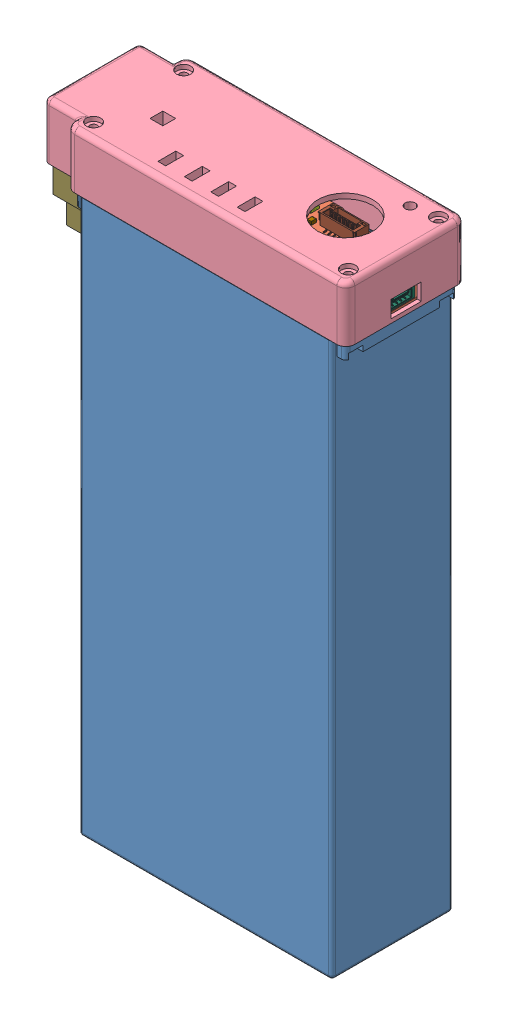
SolidWorks assembly 总装, configuration 默认. Lengths in mm.
Overall size (93.2 180.5 42.06).
174 component instances, 30 part files, 34 mates.
Components (placement in the parent):
- 电池组主外壳-1: 电池组主外壳 [默认] at origin size (80.2 164 35.9)
- 32700_cell-1: 32700_cell [默认] at (71.5 16.1 -16.1) x (0 0 1) z (0 -1 0) size (32.2 70.6 32.2)
- 32700_cell-2: 32700_cell [默认] at (0.9 48.3 -16.1) x (0 0 -1) z (0 -1 0) size (32.2 70.6 32.2)
- 32700_cell-3: 32700_cell [默认] at (71.5 80.5 -16.1) x (0 -0.381849 0.924225) z (0 -0.924225 -0.381849) size (32.2 70.6 32.2)
- 32700_cell-4: 32700_cell [默认] at (0.9 112.7 -16.1) x (0 0.381849 -0.924225) z (0 -0.924225 -0.381849) size (32.2 70.6 32.2)
- 32700_cell-5: 32700_cell [默认] at (71.5 144.9 -16.1) x (0 -0.38232 0.92403) z (0 -0.92403 -0.38232) size (32.2 70.6 32.2)
- 铜带45x10x0.45-1: 铜带45x10x0.45 [默认] at (0.9 9.7 -11.1) x (0 1 0) z (0 0 1) size (45 0.45 10)
- 铜带45x10x0.45-2: 铜带45x10x0.45 [默认] at (71.5 86.9 -11.1) x (0 -1 0) z (0 0 1) size (45 0.45 10)
- 铜带45x10x0.45-3: 铜带45x10x0.45 [默认] at (0.9 74.1 -11.1) x (0 1 0) z (0 0 1) size (45 0.45 10)
- 铜带45x10x0.45-4: 铜带45x10x0.45 [默认] at (71.95 106.3 -11.1) x (0 1 0) z (0 0 1) size (45 0.45 10)
- 面板盖-1: 面板盖 [默认] at (31.3994 162.5 -15.9507) size (93.2 16.5 35.7)
- 3D_PCB2_2026-02-08-1: 3D_PCB2_2026-02-08 [默认] at (-4.1002 162.5 0.0001) x (1 0 0) z (0 1 0) size (90.37 32.87 28.1)
  - 3D_PCB2_2026-02-08.step-1: 3D_PCB2_2026-02-08.step [默认] at origin size (90.37 32.87 15)
    - WmRV-R84-R2512.step-1: WmRV-R84-R2512.step [默认] at (22.1172 24.7766 1.6001) x (0 1 0) z (0 0 1) size (6.3 3.2 0.61)
      - COMPOUND.step-1: COMPOUND.step [默认] at origin size (6.3 3.2 0.61)
    - WmRV-R3-R0603.step-1: WmRV-R3-R0603.step [默认] at (27.4493 25.0191 1.6001) x (-1 0 0) z (0 0 1) size (1.62 0.81 0.45)
      - COMPOUND-0.step-1: COMPOUND-0.step [默认] at origin size (1.62 0.81 0.45)
    - WmRV-R4-R0603.step-1: WmRV-R4-R0603.step [默认] at (27.4321 26.4161 1.6001) x (-1 0 0) z (0 0 1) size (1.62 0.81 0.45)
      - COMPOUND-0.step-1: COMPOUND-0.step [默认] at origin size (1.62 0.81 0.45)
    - WmRV-R5-R0603.step-1: WmRV-R5-R0603.step [默认] at (30.3531 26.4161 1.6001) size (1.62 0.81 0.45)
      - COMPOUND-0.step-1: COMPOUND-0.step [默认] at origin size (1.62 0.81 0.45)
    - WmRV-R6-R0603.step-1: WmRV-R6-R0603.step [默认] at (30.3531 25.0191 1.6001) size (1.62 0.81 0.45)
      - COMPOUND-0.step-1: COMPOUND-0.step [默认] at origin size (1.62 0.81 0.45)
    - WmRV-R8-R0603.step-1: WmRV-R8-R0603.step [默认] at (30.3853 22.1925 1.6001) size (1.62 0.81 0.45)
      - COMPOUND-0.step-1: COMPOUND-0.step [默认] at origin size (1.62 0.81 0.45)
    - WmRV-R9-R0603.step-1: WmRV-R9-R0603.step [默认] at (30.3531 20.828 1.6001) size (1.62 0.81 0.45)
      - COMPOUND-0.step-1: COMPOUND-0.step [默认] at origin size (1.62 0.81 0.45)
    - WmRV-R10-R0603.step-1: WmRV-R10-R0603.step [默认] at (27.4321 22.225 1.6001) x (-1 0 0) z (0 0 1) size (1.62 0.81 0.45)
      - COMPOUND-0.step-1: COMPOUND-0.step [默认] at origin size (1.62 0.81 0.45)
    - WmRV-R11-R0603.step-1: WmRV-R11-R0603.step [默认] at (27.4321 20.828 1.6001) x (-1 0 0) z (0 0 1) size (1.62 0.81 0.45)
      - COMPOUND-0.step-1: COMPOUND-0.step [默认] at origin size (1.62 0.81 0.45)
    - WmRV-R12-R0603.step-1: WmRV-R12-R0603.step [默认] at (33.9091 16.383 1.6001) x (0 1 0) z (0 0 1) size (1.62 0.81 0.45)
      - COMPOUND-0.step-1: COMPOUND-0.step [默认] at origin size (1.62 0.81 0.45)
    - WmRV-R13-R0603.step-1: WmRV-R13-R0603.step [默认] at (35.3061 16.383 1.6001) x (0 1 0) z (0 0 1) size (1.62 0.81 0.45)
      - COMPOUND-0.step-1: COMPOUND-0.step [默认] at origin size (1.62 0.81 0.45)
    - WmRV-R20-R0603.step-1: WmRV-R20-R0603.step [默认] at (26.8015 15.6931 1.6001) size (1.62 0.81 0.45)
      - COMPOUND-0.step-1: COMPOUND-0.step [默认] at origin size (1.62 0.81 0.45)
    - WmRV-R21-R0603.step-1: WmRV-R21-R0603.step [默认] at (26.7894 17.2153 1.6001) size (1.62 0.81 0.45)
      - COMPOUND-0.step-1: COMPOUND-0.step [默认] at origin size (1.62 0.81 0.45)
    - WmRV-R22-R0603.step-1: WmRV-R22-R0603.step [默认] at (37.4651 27.5591 1.6001) x (0 -1 0) z (0 0 1) size (1.62 0.81 0.45)
      - COMPOUND-0.step-1: COMPOUND-0.step [默认] at origin size (1.62 0.81 0.45)
    - WmRV-R23-R0603.step-1: WmRV-R23-R0603.step [默认] at (38.8621 27.5591 1.6001) x (0 -1 0) z (0 0 1) size (1.62 0.81 0.45)
      - COMPOUND-0.step-1: COMPOUND-0.step [默认] at origin size (1.62 0.81 0.45)
    - WmRV-R24-R0603.step-1: WmRV-R24-R0603.step [默认] at (36.0681 27.5591 1.6001) x (0 -1 0) z (0 0 1) size (1.62 0.81 0.45)
      - COMPOUND-0.step-1: COMPOUND-0.step [默认] at origin size (1.62 0.81 0.45)
    - WmRV-R25-R0603.step-1: WmRV-R25-R0603.step [默认] at (17.761 21.4915 1.6001) x (-1 0 0) z (0 0 1) size (1.62 0.81 0.45)
      - COMPOUND-0.step-1: COMPOUND-0.step [默认] at origin size (1.62 0.81 0.45)
    - WmRV-R26-R0603.step-1: WmRV-R26-R0603.step [默认] at (39.5952 29.8217 1.6001) x (-1 0 0) z (0 0 1) size (1.62 0.81 0.45)
      - COMPOUND-0.step-1: COMPOUND-0.step [默认] at origin size (1.62 0.81 0.45)
    - WmRV-R27-R0603.step-1: WmRV-R27-R0603.step [默认] at (40.2591 27.5591 1.6001) x (0 -1 0) z (0 0 1) size (1.62 0.81 0.45)
      - COMPOUND-0.step-1: COMPOUND-0.step [默认] at origin size (1.62 0.81 0.45)
    - WmRV-R31-R0603.step-1: WmRV-R31-R0603.step [默认] at (47.0294 12.1883 1.6001) x (0 1 0) z (0 0 1) size (1.62 0.81 0.45)
      - COMPOUND-0.step-1: COMPOUND-0.step [默认] at origin size (1.62 0.81 0.45)
    - WmRV-R32-R0603.step-1: WmRV-R32-R0603.step [默认] at (45.3784 12.1883 1.6001) x (0 1 0) z (0 0 1) size (1.62 0.81 0.45)
      - COMPOUND-0.step-1: COMPOUND-0.step [默认] at origin size (1.62 0.81 0.45)
    - WmRV-R33-R0603.step-1: WmRV-R33-R0603.step [默认] at (50.3315 12.1883 1.6001) x (0 1 0) z (0 0 1) size (1.62 0.81 0.45)
      - COMPOUND-0.step-1: COMPOUND-0.step [默认] at origin size (1.62 0.81 0.45)
    - WmRV-R34-R0603.step-1: WmRV-R34-R0603.step [默认] at (48.6804 12.1883 1.6001) x (0 1 0) z (0 0 1) size (1.62 0.81 0.45)
      - COMPOUND-0.step-1: COMPOUND-0.step [默认] at origin size (1.62 0.81 0.45)
    - WmRV-R35-R0603.step-1: WmRV-R35-R0603.step [默认] at (53.6335 12.1883 1.6001) x (0 1 0) z (0 0 1) size (1.62 0.81 0.45)
      - COMPOUND-0.step-1: COMPOUND-0.step [默认] at origin size (1.62 0.81 0.45)
    - WmRV-R36-R0603.step-1: WmRV-R36-R0603.step [默认] at (51.9825 12.1883 1.6001) x (0 1 0) z (0 0 1) size (1.62 0.81 0.45)
      - COMPOUND-0.step-1: COMPOUND-0.step [默认] at origin size (1.62 0.81 0.45)
    - WmRV-R37-R0603.step-1: WmRV-R37-R0603.step [默认] at (56.9355 12.1883 1.6001) x (0 1 0) z (0 0 1) size (1.62 0.81 0.45)
      - COMPOUND-0.step-1: COMPOUND-0.step [默认] at origin size (1.62 0.81 0.45)
    - WmRV-R38-R0603.step-1: WmRV-R38-R0603.step [默认] at (55.2845 12.1883 1.6001) x (0 1 0) z (0 0 1) size (1.62 0.81 0.45)
      - COMPOUND-0.step-1: COMPOUND-0.step [默认] at origin size (1.62 0.81 0.45)
    - WmRV-R39-R0603.step-1: WmRV-R39-R0603.step [默认] at (60.2375 12.1883 1.6001) x (0 1 0) z (0 0 1) size (1.62 0.81 0.45)
      - COMPOUND-0.step-1: COMPOUND-0.step [默认] at origin size (1.62 0.81 0.45)
    - WmRV-R40-R0603.step-1: WmRV-R40-R0603.step [默认] at (58.5865 12.1883 1.6001) x (0 1 0) z (0 0 1) size (1.62 0.81 0.45)
      - COMPOUND-0.step-1: COMPOUND-0.step [默认] at origin size (1.62 0.81 0.45)
    - WmRV-R15-R0603.step-1: WmRV-R15-R0603.step [默认] at (36.4491 12.065 1.6001) x (-1 0 0) z (0 0 1) size (1.62 0.81 0.45)
      - COMPOUND-0.step-1: COMPOUND-0.step [默认] at origin size (1.62 0.81 0.45)
    - WmRV-R17-R0603.step-1: WmRV-R17-R0603.step [默认] at (32.7017 12.2384 1.6001) size (1.62 0.81 0.45)
      - COMPOUND-0.step-1: COMPOUND-0.step [默认] at origin size (1.62 0.81 0.45)
    - WmRV-R79-R0603.step-1: WmRV-R79-R0603.step [默认] at (33.0941 5.1797 1.6001) x (0 1 0) z (0 0 1) size (1.62 0.81 0.45)
      - COMPOUND-0.step-1: COMPOUND-0.step [默认] at origin size (1.62 0.81 0.45)
    - WmRV-R80-R0603.step-1: WmRV-R80-R0603.step [默认] at (25.3019 5.1441 1.6001) x (0 1 0) z (0 0 1) size (1.62 0.81 0.45)
      - COMPOUND-0.step-1: COMPOUND-0.step [默认] at origin size (1.62 0.81 0.45)
    - WmRV-R81-R0603.step-1: WmRV-R81-R0603.step [默认] at (48.7218 4.9516 1.6001) x (0 1 0) z (0 0 1) size (1.62 0.81 0.45)
      - COMPOUND-0.step-1: COMPOUND-0.step [默认] at origin size (1.62 0.81 0.45)
    - WmRV-R82-R0603.step-1: WmRV-R82-R0603.step [默认] at (41.0176 5.0593 1.6001) x (0 1 0) z (0 0 1) size (1.62 0.81 0.45)
      - COMPOUND-0.step-1: COMPOUND-0.step [默认] at origin size (1.62 0.81 0.45)
    - WmRV-R86-R0603.step-1: WmRV-R86-R0603.step [默认] at (74.961 22.2365 1.6001) x (0 -1 0) z (0 0 1) size (1.62 0.81 0.45)
      - COMPOUND-0.step-1: COMPOUND-0.step [默认] at origin size (1.62 0.81 0.45)
    - WmRV-R85-R0603.step-1: WmRV-R85-R0603.step [默认] at (68.0472 12.6732 1.6001) x (0 -1 0) z (0 0 1) size (1.62 0.81 0.45)
      - COMPOUND-0.step-1: COMPOUND-0.step [默认] at origin size (1.62 0.81 0.45)
    - WmRV-R87-R0603.step-1: WmRV-R87-R0603.step [默认] at (15.6463 12.7266 1.6001) x (0 1 0) z (0 0 1) size (1.62 0.81 0.45)
      - COMPOUND-0.step-1: COMPOUND-0.step [默认] at origin size (1.62 0.81 0.45)
    - WmRV-R88-R0603.step-1: WmRV-R88-R0603.step [默认] at (60.1459 23.4729 1.6001) size (1.62 0.81 0.45)
      - COMPOUND-0.step-1: COMPOUND-0.step [默认] at origin size (1.62 0.81 0.45)
    - WmRV-R2-R0603.step-1: WmRV-R2-R0603.step [默认] at (30.3531 23.622 1.6001) x (-1 0 0) z (0 0 1) size (1.62 0.81 0.45)
      - COMPOUND-0.step-1: COMPOUND-0.step [默认] at origin size (1.62 0.81 0.45)
    - WmRV-SW15.step-1: WmRV-SW15.step [默认] at (70.751 28.5292 1.6001) x (-1 0 0) z (0 0 1) size (4.65 3.3 2.52)
      - SW-SMD_4P-L4.2-W3.2-P2.15-LS4.6-1.step-1: SW-SMD_4P-L4.2-W3.2-P2.15-LS4.6-1.step [默认] at origin size (4.65 3.3 2.52)
        - SOLID.step-1: SOLID.step [默认] at origin size (4.65 3.3 2.52)
        - SOLID-1.step-1: SOLID-1.step [默认] at origin size (4.2 3.3 0.19)
    - WmRV-R76-R0805.step-1: WmRV-R76-R0805.step [默认] at (42.2591 24.765 1.6001) size (2 1.3 0.61)
      - COMPOUND-2.step-1: COMPOUND-2.step [默认] at origin size (2 1.3 0.61)
    - WmRV-SW16.step-1: WmRV-SW16.step [默认] at (11.6698 14.2952 1.6001) x (-1 0 0) z (0 0 1) size (5.8 5.8 13.6)
      - SW-TH_5.8ZSGT.step-1: SW-TH_5.8ZSGT.step [默认] at origin size (5.8 5.8 13.6)
        - SOLID-3.step-1: SOLID-3.step [默认] at origin size (5.8 5.8 7.6)
        - SOLID-4.step-1: SOLID-4.step [默认] at origin size (5.8 5.8 9.74)
    - WmRV-R65-R1206.step-1: WmRV-R65-R1206.step [默认] at (49.7282 19.8084 1.6001) x (0 1 0) z (0 0 1) size (3.2 1.6 0.56)
      - COMPOUND-5.step-1: COMPOUND-5.step [默认] at origin size (3.2 1.6 0.56)
    - WmRV-R66-R1206.step-1: WmRV-R66-R1206.step [默认] at (53.062 19.8084 1.6001) x (0 1 0) z (0 0 1) size (3.2 1.6 0.56)
      - COMPOUND-5.step-1: COMPOUND-5.step [默认] at origin size (3.2 1.6 0.56)
    - WmRV-R67-R1206.step-1: WmRV-R67-R1206.step [默认] at (56.3957 19.8084 1.6001) x (0 1 0) z (0 0 1) size (3.2 1.6 0.56)
      - COMPOUND-5.step-1: COMPOUND-5.step [默认] at origin size (3.2 1.6 0.56)
    - WmRV-R68-R1206.step-1: WmRV-R68-R1206.step [默认] at (59.7295 19.8084 1.6001) x (0 1 0) z (0 0 1) size (3.2 1.6 0.56)
      - COMPOUND-5.step-1: COMPOUND-5.step [默认] at origin size (3.2 1.6 0.56)
    - WmRV-R64-R1206.step-1: WmRV-R64-R1206.step [默认] at (46.3944 19.8084 1.6001) x (0 1 0) z (0 0 1) size (3.2 1.6 0.56)
      - COMPOUND-5.step-1: COMPOUND-5.step [默认] at origin size (3.2 1.6 0.56)
    - WmRV-R16-RES-TH_L2.5-W2.5-P1.70-D0.3.step-1: WmRV-R16-RES-TH_L2.5-W2.5-P1.70-D0.3.step [默认] at (36.3221 9.906 1.6001) x (-1 0 0) z (0 0 1) size (2.52 2.5 7.2)
      - COMPOUND-6.step-1: COMPOUND-6.step [默认] at origin size (2.52 2.5 7.2)
    - WmRV-R14-RES-TH_L2.5-W2.5-P1.70-D0.3.step-1: WmRV-R14-RES-TH_L2.5-W2.5-P1.70-D0.3.step [默认] at (32.7661 9.906 1.6001) size (2.52 2.5 7.2)
      - COMPOUND-6.step-1: COMPOUND-6.step [默认] at origin size (2.52 2.5 7.2)
    - WmRV-U13-QFN-28_L4.0-W4.0-P0.40-BL-EP2.8.step-1: WmRV-U13-QFN-28_L4.0-W4.0-P0.40-BL-EP2.8.step [默认] at (70.06 17.4212 1.6001) x (-1 0 0) z (0 0 1) size (4 4 0.72)
      - COMPOUND-7.step-1: COMPOUND-7.step [默认] at origin size (4 4 0.72)
    - WmRV-U14-CONN-SMD_4P-P1.25_XUNPU_WAFER-GH1.25-4PWB.step-1: WmRV-U14-CONN-SMD_4P-P1.25_XUNPU_WAFER-GH1.25-4PWB.step [默认] at (76.8352 16.45 1.6001) x (0 1 0) z (0 0 1) size (8.25 5 4.35)
      - COMPOUND-8.step-1: COMPOUND-8.step [默认] at origin size (8.25 5 4.35)
    - WmRV-Q7-SOT-23-3_L2.9-W1.3-P1.90-LS2.4-BR.step-1: WmRV-Q7-SOT-23-3_L2.9-W1.3-P1.90-LS2.4-BR.step [默认] at (56.2111 15.5381 1.6001) x (0 -1 0) z (0 0 1) size (2.5 2.89 1.05)
      - COMPOUND-9.step-1: COMPOUND-9.step [默认] at origin size (2.5 2.89 1.05)
    - WmRV-Q8-SOT-23-3_L2.9-W1.3-P1.90-LS2.4-BR.step-1: WmRV-Q8-SOT-23-3_L2.9-W1.3-P1.90-LS2.4-BR.step [默认] at (59.5257 15.5381 1.6001) x (0 -1 0) z (0 0 1) size (2.5 2.89 1.05)
      - COMPOUND-9.step-1: COMPOUND-9.step [默认] at origin size (2.5 2.89 1.05)
    - WmRV-Q9-SOT-23-3_L2.9-W1.3-P1.90-LS2.4-BR.step-1: WmRV-Q9-SOT-23-3_L2.9-W1.3-P1.90-LS2.4-BR.step [默认] at (49.582 15.5381 1.6001) x (0 -1 0) z (0 0 1) size (2.5 2.89 1.05)
      - COMPOUND-9.step-1: COMPOUND-9.step [默认] at origin size (2.5 2.89 1.05)
    - WmRV-Q10-SOT-23-3_L2.9-W1.3-P1.90-LS2.4-BR.step-1: WmRV-Q10-SOT-23-3_L2.9-W1.3-P1.90-LS2.4-BR.step [默认] at (46.2674 15.5381 1.6001) x (0 -1 0) z (0 0 1) size (2.5 2.89 1.05)
      - COMPOUND-9.step-1: COMPOUND-9.step [默认] at origin size (2.5 2.89 1.05)
    - WmRV-Q6-SOT-23-3_L2.9-W1.3-P1.90-LS2.4-BR.step-1: WmRV-Q6-SOT-23-3_L2.9-W1.3-P1.90-LS2.4-BR.step [默认] at (52.8966 15.5381 1.6001) x (0 -1 0) z (0 0 1) size (2.5 2.89 1.05)
      - COMPOUND-9.step-1: COMPOUND-9.step [默认] at origin size (2.5 2.89 1.05)
    - WmRV-BUTTON-CONN-SMD_3P-P1.25_XUNPU_WAFER-GH1.25-3PLB.step-1: WmRV-BUTTON-CONN-SMD_3P-P1.25_XUNPU_WAFER-GH1.25-3PLB.step [默认] at (68.2638 7.662 1.6001) size (7.06 4.95 4.2)
      - COMPOUND-10.step-1: COMPOUND-10.step [默认] at origin size (7.06 4.95 4.2)
    - WmRV-U4-QFN-28_L5.0-W5.0-P0.50-TL-EP3.3.step-1: WmRV-U4-QFN-28_L5.0-W5.0-P0.50-TL-EP3.3.step [默认] at (36.0465 22.0655 1.6001) size (5 5 0.93)
      - COMPOUND-11.step-1: COMPOUND-11.step [默认] at origin size (5 5 0.93)
    - WmRV-U12-SOIC-16_L10.3-W7.5-P1.27-LS10.3-BL.step-1: WmRV-U12-SOIC-16_L10.3-W7.5-P1.27-LS10.3-BL.step [默认] at (13.7371 5.7123 1.6001) x (0 1 0) z (0 0 1) size (10.3 10.41 2.85)
      - COMPOUND-12.step-1: COMPOUND-12.step [默认] at origin size (10.3 10.41 2.85)
    - WmRV-Board.step-1: WmRV-Board.step [默认] at origin size (90.37 32.87 1.6)
    - WmRV-D2-SMA_L4.2-W2.6-LS5.0-RD_1.step-1: WmRV-D2-SMA_L4.2-W2.6-LS5.0-RD_1.step [默认] at (9.9917 21.1675 1.6001) size (5 2.57 2.05)
    - WmRV-C33-C0805.step-1: WmRV-C33-C0805.step [默认] at (42.4181 22.733 1.6001) x (-1 0 0) z (0 0 1) size (2 1.3 1.3)
    - WmRV-Q11-DFN-8_L5.8-W4.9-P1.27-LS6.1-BL-2.step-1: WmRV-Q11-DFN-8_L5.8-W4.9-P1.27-LS6.1-BL-2.step [默认] at (15.7047 25.2897 1.6001) x (0 1 0) z (0 0 1) size (5.15 6.1 1.03)
    - WmRV-Q11-DFN-8_L5.8-W4.9-P1.27-LS6.1-BL-2.step-2: WmRV-Q11-DFN-8_L5.8-W4.9-P1.27-LS6.1-BL-2.step [默认] at (8.6597 25.278 1.6001) x (0 -1 0) z (0 0 1) size (5.15 6.1 1.03)
    - WmRV-X2-CRYSTAL-SMD_4P-L3.2-W2.5-BL.step-1: WmRV-X2-CRYSTAL-SMD_4P-L3.2-W2.5-BL.step [默认] at (70.695 22.5012 1.6001) x (-1 0 0) z (0 0 1) size (3.2 2.5 0.7)
    - WmRV-D50-SOD-123FL_L2.7-W1.8-LS3.8-RD.step-1: WmRV-D50-SOD-123FL_L2.7-W1.8-LS3.8-RD.step [默认] at (42.1641 28.0671 1.6001) x (0 1 0) z (0 0 1) size (3.7 1.8 1.14)
    - WmRV-LED5-LED-TH_L5.0-W2.5-P2.54-FD_GREEN_XL-257SYGD-L.step-1: WmRV-LED5-LED-TH_L5.0-W2.5-P2.54-FD_GREEN_XL-257SYGD-L.step [默认] at (38.7774 5.207 1.6001) x (0 1 0) z (0 0 1) size (5 2.5 15)
    - WmRV-LED5-LED-TH_L5.0-W2.5-P2.54-FD_GREEN_XL-257SYGD-L.step-2: WmRV-LED5-LED-TH_L5.0-W2.5-P2.54-FD_GREEN_XL-257SYGD-L.step [默认] at (30.9457 5.207 1.6001) x (0 1 0) z (0 0 1) size (5 2.5 15)
    - WmRV-LED5-LED-TH_L5.0-W2.5-P2.54-FD_GREEN_XL-257SYGD-L.step-3: WmRV-LED5-LED-TH_L5.0-W2.5-P2.54-FD_GREEN_XL-257SYGD-L.step [默认] at (23.114 5.207 1.6001) x (0 1 0) z (0 0 1) size (5 2.5 15)
    - WmRV-LED5-LED-TH_L5.0-W2.5-P2.54-FD_GREEN_XL-257SYGD-L.step-4: WmRV-LED5-LED-TH_L5.0-W2.5-P2.54-FD_GREEN_XL-257SYGD-L.step [默认] at (46.6091 5.207 1.6001) x (0 1 0) z (0 0 1) size (5 2.5 15)
    - WmRV-D1-SOD-323_L1.6-W1.3-LS2.7-RD.step-1: WmRV-D1-SOD-323_L1.6-W1.3-LS2.7-RD.step [默认] at (45.7201 24.384 1.6001) x (0 -1 0) z (0 0 1) size (2.65 1.3 1.1)
    - WmRV-C1-C0603.step-1: WmRV-C1-C0603.step [默认] at (34.4775 27.4985 1.6001) x (0 1 0) z (0 0 1) size (1.6 0.8 0.8)
    - WmRV-C1-C0603.step-2: WmRV-C1-C0603.step [默认] at (36.4491 13.843 1.6001) x (-1 0 0) z (0 0 1) size (1.6 0.8 0.8)
    - WmRV-C1-C0603.step-3: WmRV-C1-C0603.step [默认] at (32.701 13.9081 1.6001) size (1.6 0.8 0.8)
    - WmRV-C1-C0603.step-4: WmRV-C1-C0603.step [默认] at (29.1228 16.5302 1.6001) x (0 1 0) z (0 0 1) size (1.6 0.8 0.8)
    - WmRV-C1-C0603.step-5: WmRV-C1-C0603.step [默认] at (31.453 17.3416 1.6001) x (-1 0 0) z (0 0 1) size (1.6 0.8 0.8)
    - WmRV-C1-C0603.step-6: WmRV-C1-C0603.step [默认] at (31.5108 15.777 1.6001) x (-1 0 0) z (0 0 1) size (1.6 0.8 0.8)
    - WmRV-C1-C0603.step-7: WmRV-C1-C0603.step [默认] at (38.4811 16.383 1.6001) x (0 1 0) z (0 0 1) size (1.6 0.8 0.8)
    - WmRV-C1-C0603.step-8: WmRV-C1-C0603.step [默认] at (40.1321 16.383 1.6001) x (0 1 0) z (0 0 1) size (1.6 0.8 0.8)
    - WmRV-C1-C0603.step-9: WmRV-C1-C0603.step [默认] at (41.7831 19.304 1.6001) x (-1 0 0) z (0 0 1) size (1.6 0.8 0.8)
    - WmRV-C1-C0603.step-10: WmRV-C1-C0603.step [默认] at (41.7831 20.955 1.6001) x (-1 0 0) z (0 0 1) size (1.6 0.8 0.8)
    - WmRV-C1-C0603.step-11: WmRV-C1-C0603.step [默认] at (36.8302 16.383 1.6001) x (0 1 0) z (0 0 1) size (1.6 0.8 0.8)
    - WmRV-C1-C0603.step-12: WmRV-C1-C0603.step [默认] at (8.8836 18.8768 1.6001) x (-1 0 0) z (0 0 1) size (1.6 0.8 0.8)
    - WmRV-C1-C0603.step-13: WmRV-C1-C0603.step [默认] at (11.9171 18.9097 1.6001) x (-1 0 0) z (0 0 1) size (1.6 0.8 0.8)
    - WmRV-C1-C0603.step-14: WmRV-C1-C0603.step [默认] at (65.4491 20.2385 1.6001) size (1.6 0.8 0.8)
    - WmRV-C1-C0603.step-15: WmRV-C1-C0603.step [默认] at (72.473 25.4222 1.6001) x (-1 0 0) z (0 0 1) size (1.6 0.8 0.8)
    - WmRV-C1-C0603.step-16: WmRV-C1-C0603.step [默认] at (69.425 25.4222 1.6001) x (-1 0 0) z (0 0 1) size (1.6 0.8 0.8)
    - WmRV-C1-C0603.step-17: WmRV-C1-C0603.step [默认] at (65.4491 23.2865 1.6001) size (1.6 0.8 0.8)
    - WmRV-C1-C0603.step-18: WmRV-C1-C0603.step [默认] at (65.4491 21.7625 1.6001) x (-1 0 0) z (0 0 1) size (1.6 0.8 0.8)
    - WmRV-C1-C0603.step-19: WmRV-C1-C0603.step [默认] at (69.8501 12.7 1.6001) x (0 -1 0) z (0 0 1) size (1.6 0.8 0.8)
    - WmRV-C1-C0603.step-20: WmRV-C1-C0603.step [默认] at (20.6738 1.8052 1.6001) x (0 -1 0) z (0 0 1) size (1.6 0.8 0.8)
    - WmRV-C1-C0603.step-21: WmRV-C1-C0603.step [默认] at (6.7038 1.8052 1.6001) x (0 1 0) z (0 0 1) size (1.6 0.8 0.8)
    - WmRV-C1-C0603.step-22: WmRV-C1-C0603.step [默认] at (71.5101 12.7137 1.6001) x (0 -1 0) z (0 0 1) size (1.6 0.8 0.8)
    - WmRV-C1-C0603.step-23: WmRV-C1-C0603.step [默认] at (32.9535 27.4985 1.6001) x (0 1 0) z (0 0 1) size (1.6 0.8 0.8)
    - WmRV-U6-CONN-SMD_6P-P1.25_XUNPU_WAFER-GH1.25-6PLB.step-1: WmRV-U6-CONN-SMD_6P-P1.25_XUNPU_WAFER-GH1.25-6PLB.step [默认] at (53.0861 25.7811 1.6001) x (-1 0 0) z (0 0 1) size (10.8 4.94 4.03)
  - XT60-2+4-1: XT60-2+4 [默认] at (0.0127 3.6627 0) x (-1 0 0) z (0 -1 0) size (10.2 19.9 25.6)
Mates (geometry in assembly coordinates):
- 距离1: distance = 0.5 mm anti-aligned: plane of 32700_cell-1 through (71.5 16.1 -16.1) normal (1 0 0); plane of 电池组主外壳-1 through (72 162.5 0) normal (-1 0 0)
- 相切2: tangent anti-aligned: plane of 电池组主外壳-1 through (0 162.5 0) normal (0 0 -1); cylinder of 32700_cell-1 through (0.9 16.1 -16.1) axis (1 0 0) radius 16.1
- 相切3: tangent anti-aligned: plane of 电池组主外壳-1 through (0 0 0) normal (0 1 0); cylinder of 32700_cell-1 through (0.9 16.1 -16.1) axis (1 0 0) radius 16.1
- 重合3: coincident aligned: plane of 32700_cell-1 through (0.9 16.1 -16.1) normal (-1 0 0); plane of 32700_cell-2 through (0.9 48.3 -16.1) normal (-1 0 0)
- 相切4: tangent anti-aligned: plane of 电池组主外壳-1 through (0 162.5 0) normal (0 0 -1); cylinder of 32700_cell-2 through (71.5 48.3 -16.1) axis (-1 0 0) radius 16.1
- 相切5: tangent anti-aligned: cylinder of 32700_cell-1 through (0.9 16.1 -16.1) axis (1 0 0) radius 16.1; cylinder of 32700_cell-2 through (71.5 48.3 -16.1) axis (-1 0 0) radius 16.1
- 重合4: coincident aligned: plane of 32700_cell-2 through (0.9 48.3 -16.1) normal (-1 0 0); plane of 32700_cell-3 through (0.9 80.5 -16.1) normal (-1 0 0)
- 相切6: tangent anti-aligned: cylinder of 32700_cell-2 through (71.5 48.3 -16.1) axis (-1 0 0) radius 16.1; cylinder of 32700_cell-3 through (0.9 80.5 -16.1) axis (1 0 0) radius 16.1
- 相切7: tangent anti-aligned: plane of 电池组主外壳-1 through (0 162.5 0) normal (0 0 -1); cylinder of 32700_cell-3 through (0.9 80.5 -16.1) axis (1 0 0) radius 16.1
- 重合5: coincident aligned: plane of 32700_cell-3 through (0.9 80.5 -16.1) normal (-1 0 0); plane of 32700_cell-4 through (0.9 112.7 -16.1) normal (-1 0 0)
- 相切8: tangent anti-aligned: cylinder of 32700_cell-3 through (0.9 80.5 -16.1) axis (1 0 0) radius 16.1; cylinder of 32700_cell-4 through (71.5 112.7 -16.1) axis (-1 0 0) radius 16.1
- 相切9: tangent anti-aligned: plane of 电池组主外壳-1 through (0 162.5 0) normal (0 0 -1); cylinder of 32700_cell-4 through (71.5 112.7 -16.1) axis (-1 0 0) radius 16.1
- 重合6: coincident aligned: plane of 32700_cell-4 through (0.9 112.7 -16.1) normal (-1 0 0); plane of 32700_cell-5 through (0.9 144.9 -16.1) normal (-1 0 0)
- 相切10: tangent anti-aligned: cylinder of 32700_cell-4 through (71.5 112.7 -16.1) axis (-1 0 0) radius 16.1; cylinder of 32700_cell-5 through (0.9 144.9 -16.1) axis (1 0 0) radius 16.1
- 相切11: tangent anti-aligned: plane of 电池组主外壳-1 through (0 162.5 0) normal (0 0 -1); cylinder of 32700_cell-5 through (0.9 144.9 -16.1) axis (1 0 0) radius 16.1
- 重合7: coincident anti-aligned: plane of 32700_cell-2 through (0.9 48.3 -16.1) normal (-1 0 0); plane of 铜带45x10x0.45-1 through (0.9 9.7 -11.1) normal (1 0 0)
- 平行2: parallel aligned: plane of 电池组主外壳-1 through (0 -1.5 0) normal (0 -1 0); plane of 32700_cell-1 through (71.5 16.1 -16.1) normal (0 -1 0)
- 对称1: symmetric aligned: plane of 32700_cell-1 through (71.5 16.1 -16.1) normal (0 0 1); plane of 铜带45x10x0.45-1 through (0.45 9.7 -21.1) normal (0 0 -1); plane of 铜带45x10x0.45-1 through (0.45 9.7 -11.1) normal (0 0 1)
- 宽度2: width aligned: plane of 铜带45x10x0.45-1 through (0.45 9.7 -11.1) normal (0 -1 0); plane of 铜带45x10x0.45-1 through (0.45 54.7 -11.1) normal (0 1 0); plane of 32700_cell-1 through (71.5 16.1 -16.1) normal (0 -1 0); plane of 32700_cell-2 through (0.9 48.3 -16.1) normal (0 -1 0)
- 重合12: coincident anti-aligned: plane of 32700_cell-2 through (71.5 48.3 -16.1) normal (1 0 0); plane of 铜带45x10x0.45-2 through (71.5 86.9 -11.1) normal (-1 0 0)
- 重合13: coincident aligned: plane of 铜带45x10x0.45-1 through (0.45 9.7 -21.1) normal (0 0 -1); plane of 铜带45x10x0.45-2 through (71.95 86.9 -21.1) normal (0 0 -1)
- 距离4: distance = 32.2 mm aligned: plane of 铜带45x10x0.45-2 through (71.95 41.9 -11.1) normal (0 -1 0); plane of 铜带45x10x0.45-1 through (0.45 9.7 -11.1) normal (0 -1 0)
- 重合15: coincident anti-aligned: plane of 32700_cell-3 through (0.9 80.5 -16.1) normal (-1 0 0); plane of 铜带45x10x0.45-3 through (0.9 74.1 -11.1) normal (1 0 0)
- 重合16: coincident aligned: plane of 铜带45x10x0.45-1 through (0.45 9.7 -21.1) normal (0 0 -1); plane of 铜带45x10x0.45-3 through (0.45 74.1 -21.1) normal (0 0 -1)
- 距离5: distance = 32.2 mm aligned: plane of 铜带45x10x0.45-3 through (0.45 74.1 -11.1) normal (0 -1 0); plane of 铜带45x10x0.45-2 through (71.95 41.9 -11.1) normal (0 -1 0)
- 重合18: coincident anti-aligned: plane of 32700_cell-4 through (71.5 112.7 -16.1) normal (1 0 0); plane of 铜带45x10x0.45-4 through (71.5 106.3 -11.1) normal (-1 0 0)
- 重合19: coincident aligned: plane of 铜带45x10x0.45-2 through (71.95 86.9 -21.1) normal (0 0 -1); plane of 铜带45x10x0.45-4 through (71.5 106.3 -21.1) normal (0 0 -1)
- 距离6: distance = 32.2 mm aligned: plane of 铜带45x10x0.45-4 through (71.5 106.3 -11.1) normal (0 -1 0); plane of 铜带45x10x0.45-3 through (0.45 74.1 -11.1) normal (0 -1 0)
- 重合25: coincident anti-aligned: plane of 电池组主外壳-1 through (0 162.5 0) normal (0 1 0); plane of 面板盖-1 through (-14.05 162.5 -3.9) normal (0 -1 0)
- 同心7: concentric anti-aligned: cylinder of 电池组主外壳-1 through (-2.85 158 -1.25) axis (0 1 0) radius 1.25; cylinder of 面板盖-1 through (-2.85 177.5 -1.25) axis (0 -1 0) radius 2.65
- 平行7: parallel aligned: plane of 电池组主外壳-1 through (0 162.5 1.5) normal (0 0 1); plane of 面板盖-1 through (-2.85 177.5 1.4) normal (0 0 1)
- 重合26: coincident anti-aligned: plane of 电池组主外壳-1 through (0 162.5 0) normal (0 1 0); plane of 3D_PCB2_2026-02-08-1/3D_PCB2_2026-02-08.step-1/WmRV-Board.step-1 through (31.7411 162.5 -16.5375) normal (0 -1 0)
- 同心8: concentric anti-aligned: cylinder of 电池组主外壳-1 through (73.75 157.5 -29.9) axis (0 1 0) radius 1.1; cylinder of 3D_PCB2_2026-02-08-1/3D_PCB2_2026-02-08.step-1/WmRV-Board.step-1 through (73.75 162.5 -29.9) axis (0 -1 0) radius 1.1
- 平行8: parallel aligned: plane of 电池组主外壳-1 through (0 162.5 1.5) normal (0 0 1); plane of 3D_PCB2_2026-02-08-1/3D_PCB2_2026-02-08.step-1/WmRV-Board.step-1 through (74.85 162.5 -0.0126) normal (0 0 1)
